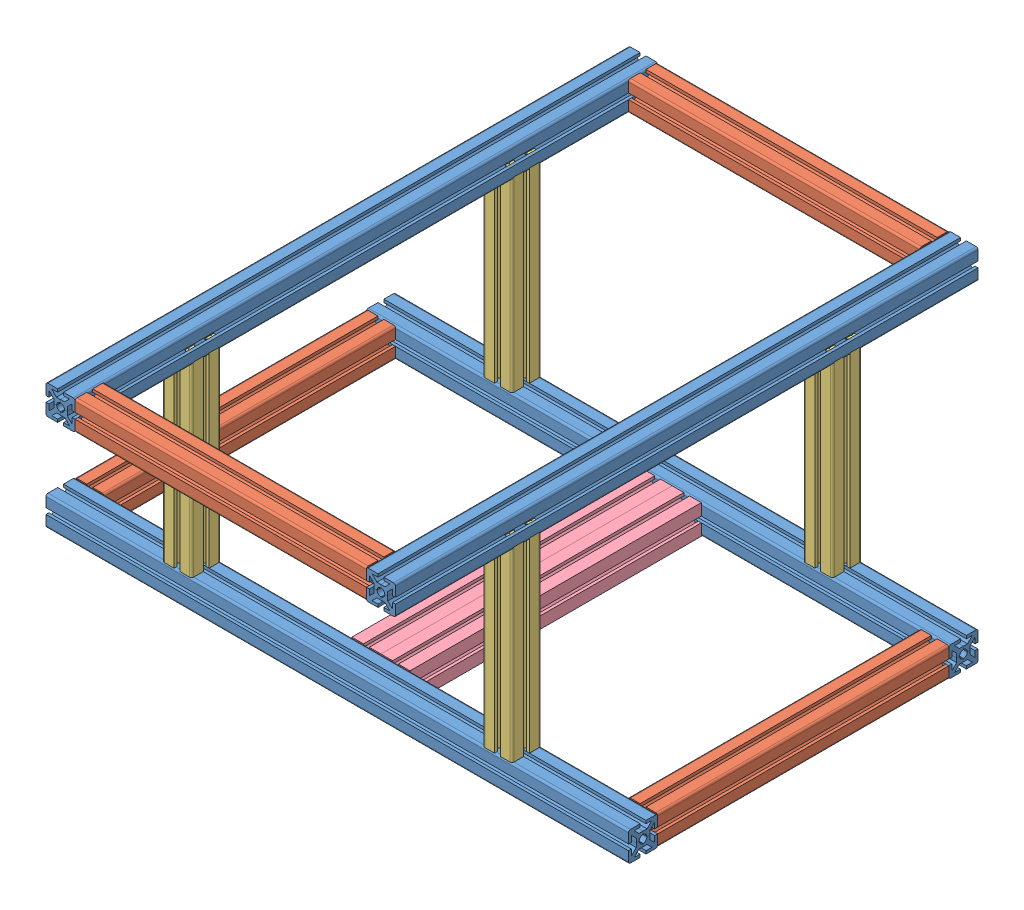
SolidWorks assembly Estructura, configuration Predeterminado. Lengths in mm.
Overall size (600 250 600).
13 component instances, 4 part files, 37 mates.
Components (placement in the parent):
- perfil 30x600-1: perfil 30x600 [Predeterminado] at (0 15 -215) x (0 0 1) z (-1 0 0) size (30 30 600)
- perfil 30x600-2: perfil 30x600 [Predeterminado] at (0 15 115) x (0 0 1) z (-1 0 0) size (30 30 600)
- perfil 30x600-3: perfil 30x600 [Predeterminado] at (-165 235 -50) size (30 30 600)
- perfil 30x600-4: perfil 30x600 [Predeterminado] at (165 235 -50) x (-1 0 0) z (0 0 -1) size (30 30 600)
- perfil 30x300-1: perfil 30x300 [Predeterminado] at (285 15 -50) size (30 30 300)
- perfil 30x300-2: perfil 30x300 [Predeterminado] at (-285 15 -50) size (30 30 300)
- perfil 30x300-5: perfil 30x300 [Predeterminado] at (0 235 235) x (0 0 1) z (-1 0 0) size (30 30 300)
- perfil 30x300-6: perfil 30x300 [Predeterminado] at (0 235 -335) x (0 0 1) z (-1 0 0) size (30 30 300)
- perfil 30x200-1: perfil 30x200 [Predeterminado] at (165 130 -215) x (1 0 0) z (0 1 0) size (30 30 200)
- perfil 30x200-2: perfil 30x200 [Predeterminado] at (165 130 115) x (1 0 0) z (0 1 0) size (30 30 200)
- perfil 30x200-3: perfil 30x200 [Predeterminado] at (-165 130 -215) x (1 0 0) z (0 1 0) size (30 30 200)
- perfil 30x200-4: perfil 30x200 [Predeterminado] at (-165 130 115) x (1 0 0) z (0 1 0) size (30 30 200)
- perfil 60x30x300-1: perfil 60x30x300 [Predeterminado] at (0 15 -50) size (60 30 300)
Mates (geometry in assembly coordinates):
- Coincidente7: coincident aligned: plane of perfil 30x600-1 through (300 15 -215) normal (1 0 0); plane of perfil 30x600-2 through (300 15 115) normal (1 0 0)
- Coincidente15: coincident anti-aligned: plane of perfil 30x600-1 through (-300 18 -200) normal (0 0 1); plane of perfil 30x300-1 through (285 15 -200) normal (0 0 -1)
- Coincidente16: coincident aligned: plane of perfil 30x600-1 through (-300 30 -212) normal (0 1 0); plane of perfil 30x300-1 through (282 30 100) normal (0 1 0)
- Coincidente17: coincident aligned: plane of perfil 30x600-1 through (300 15 -215) normal (1 0 0); plane of perfil 30x300-1 through (300 18 100) normal (1 0 0)
- Coincidente19: coincident anti-aligned: plane of perfil 30x600-2 through (-300 18 100) normal (0 0 -1); plane of perfil 30x300-1 through (285 15 100) normal (0 0 1)
- Coincidente20: coincident aligned: plane of perfil 30x600-2 through (300 15 115) normal (1 0 0); plane of perfil 30x300-1 through (300 18 100) normal (1 0 0)
- Coincidente21: coincident aligned: plane of perfil 30x600-2 through (-300 30 112) normal (0 1 0); plane of perfil 30x300-1 through (288 30 100) normal (0 1 0)
- Coincidente23: coincident aligned: plane of perfil 30x600-1 through (-300 30 -212) normal (0 1 0); plane of perfil 30x300-2 through (-282 30 100) normal (0 1 0)
- Coincidente24: coincident anti-aligned: plane of perfil 30x600-1 through (-300 18 -200) normal (0 0 1); plane of perfil 30x300-2 through (-285 15 -200) normal (0 0 -1)
- Coincidente25: coincident aligned: plane of perfil 30x600-1 through (-300 15 -215) normal (-1 0 0); plane of perfil 30x300-2 through (-300 18 100) normal (-1 0 0)
- Coincidente26: coincident anti-aligned: plane of perfil 30x600-4 through (150 238 -350) normal (-1 0 0); plane of perfil 30x300-5 through (150 235 235) normal (1 0 0)
- Coincidente27: coincident aligned: plane of perfil 30x600-4 through (162 250 -350) normal (0 1 0); plane of perfil 30x300-5 through (-150 250 232) normal (0 1 0)
- Coincidente28: coincident aligned: plane of perfil 30x600-4 through (165 235 250) normal (0 0 1); plane of perfil 30x300-5 through (-150 238 250) normal (0 0 1)
- Coincidente29: coincident aligned: plane of perfil 30x600-3 through (-165 235 250) normal (0 0 1); plane of perfil 30x300-5 through (-150 238 250) normal (0 0 1)
- Coincidente30: coincident anti-aligned: plane of perfil 30x600-3 through (-150 238 250) normal (1 0 0); plane of perfil 30x300-5 through (-150 235 235) normal (-1 0 0)
- Coincidente31: coincident aligned: plane of perfil 30x600-3 through (-162 250 250) normal (0 1 0); plane of perfil 30x300-5 through (-150 250 232) normal (0 1 0)
- Coincidente32: coincident aligned: plane of perfil 30x600-4 through (162 250 -350) normal (0 1 0); plane of perfil 30x300-6 through (-150 250 -338) normal (0 1 0)
- Coincidente33: coincident aligned: plane of perfil 30x600-4 through (165 235 -350) normal (0 0 -1); plane of perfil 30x300-6 through (-150 238 -350) normal (0 0 -1)
- Coincidente34: coincident anti-aligned: plane of perfil 30x600-4 through (150 238 -350) normal (-1 0 0); plane of perfil 30x300-6 through (150 235 -335) normal (1 0 0)
- Distancia5: distance = 120 mm aligned: plane of perfil 30x400-6 through (-150 238 -350) normal (0 0 -1); plane of perfil 30x600-1 through (-300 18 -230) normal (0 0 -1)
- Distancia6: distance = 120 mm aligned: plane of perfil 30x600-4 through (180 238 -350) normal (1 0 0); plane of perfil 30x400-1 through (300 18 100) normal (1 0 0)
- Distancia7: distance = 220 mm aligned: plane of perfil 30x400-5 through (-150 250 238) normal (0 1 0); plane of perfil 30x600-2 through (-300 30 118) normal (0 1 0)
- Coincidente38: coincident anti-aligned: plane of perfil 30x600-1 through (-300 30 -212) normal (0 1 0); plane of perfil 30x200-1 through (165 30 -215) normal (0 -1 0)
- Coincidente39: coincident aligned: plane of perfil 30x600-1 through (-300 18 -230) normal (0 0 -1); plane of perfil 30x200-1 through (162 230 -230) normal (0 0 -1)
- Coincidente40: coincident aligned: plane of perfil 30x600-4 through (180 238 -350) normal (1 0 0); plane of perfil 30x200-1 through (180 230 -218) normal (1 0 0)
- Coincidente41: coincident anti-aligned: plane of perfil 30x600-2 through (-300 30 118) normal (0 1 0); plane of perfil 30x200-2 through (165 30 115) normal (0 -1 0)
- Coincidente42: coincident aligned: plane of perfil 30x600-2 through (-300 18 130) normal (0 0 1); plane of perfil 30x200-2 through (168 230 130) normal (0 0 1)
- Coincidente43: coincident aligned: plane of perfil 30x600-4 through (180 232 -350) normal (1 0 0); plane of perfil 30x200-2 through (180 230 118) normal (1 0 0)
- Coincidente44: coincident anti-aligned: plane of perfil 30x600-1 through (-300 30 -218) normal (0 1 0); plane of perfil 30x200-3 through (-165 30 -215) normal (0 -1 0)
- Coincidente45: coincident aligned: plane of perfil 30x600-1 through (-300 18 -230) normal (0 0 -1); plane of perfil 30x200-3 through (-168 230 -230) normal (0 0 -1)
- Coincidente46: coincident aligned: plane of perfil 30x600-3 through (-180 232 250) normal (-1 0 0); plane of perfil 30x200-3 through (-180 230 -218) normal (-1 0 0)
- Coincidente47: coincident anti-aligned: plane of perfil 30x600-2 through (-300 30 118) normal (0 1 0); plane of perfil 30x200-4 through (-165 30 115) normal (0 -1 0)
- Coincidente48: coincident aligned: plane of perfil 30x600-3 through (-180 232 250) normal (-1 0 0); plane of perfil 30x200-4 through (-180 230 118) normal (-1 0 0)
- Coincidente49: coincident aligned: plane of perfil 30x600-2 through (-300 18 130) normal (0 0 1); plane of perfil 30x200-4 through (-168 230 130) normal (0 0 1)
- Coincidente50: coincident anti-aligned: plane of perfil 30x600-2 through (-300 18 100) normal (0 0 -1); plane of perfil 60x30x300-1 through (0 15 100) normal (0 0 1)
- Coincidente51: coincident aligned: plane of perfil 30x600-2 through (-300 30 112) normal (0 1 0); plane of perfil 60x30x300-1 through (-3 30 100) normal (0 1 0)
- Distancia8: distance = 0 mm: plane of perfil 60x30x300-1 through (0 15 -50) normal (1 0 0); point of assembly
